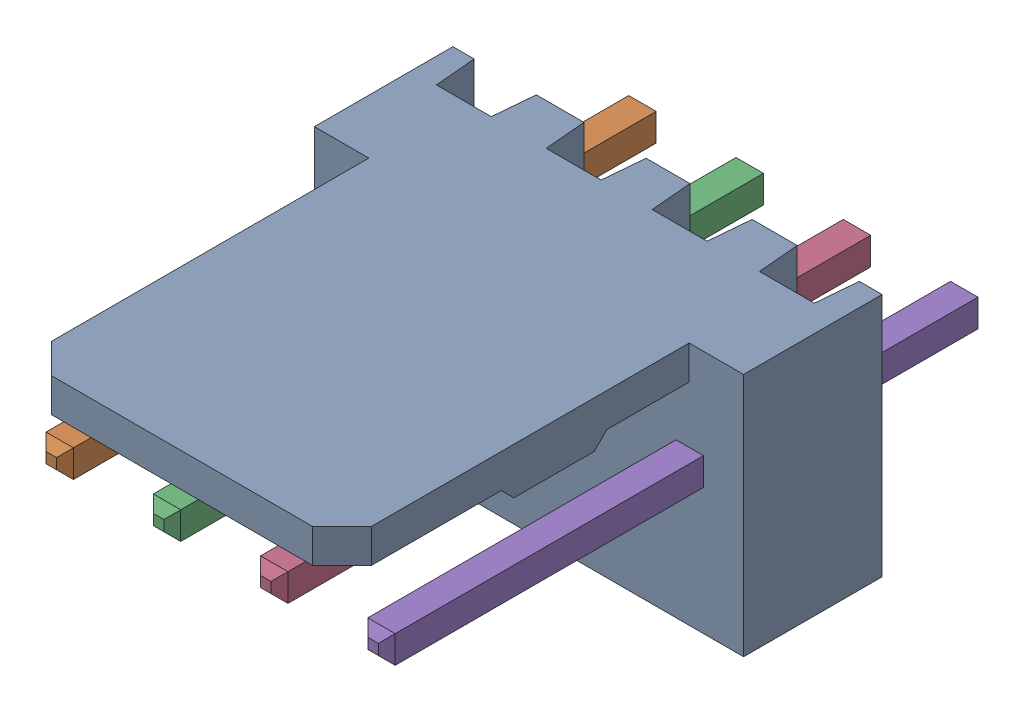
SolidWorks assembly Molex PCB 4 pin v3_3, configuration Default. Lengths in mm.
Overall size (10.16 5.79 14.92).
5 component instances, 2 part files, 0 mates.
Components (placement in the parent):
- BASE9710016-1: BASE9710016 [Default] at (2.54 2.895 -8.22) size (10.16 5.79 11.5)
- PINO9710016-1: PINO9710016 [Default] at (1.27 3.325 -0.72) size (0.65 0.65 14.2)
- PINO9710016-2: PINO9710016 [Default] at (3.81 3.325 -0.72) size (0.65 0.65 14.2)
- PINO9710016-3: PINO9710016 [Default] at (6.35 3.325 -0.72) size (0.65 0.65 14.2)
- PINO9710016-4: PINO9710016 [Default] at (8.89 3.325 -0.72) size (0.65 0.65 14.2)
